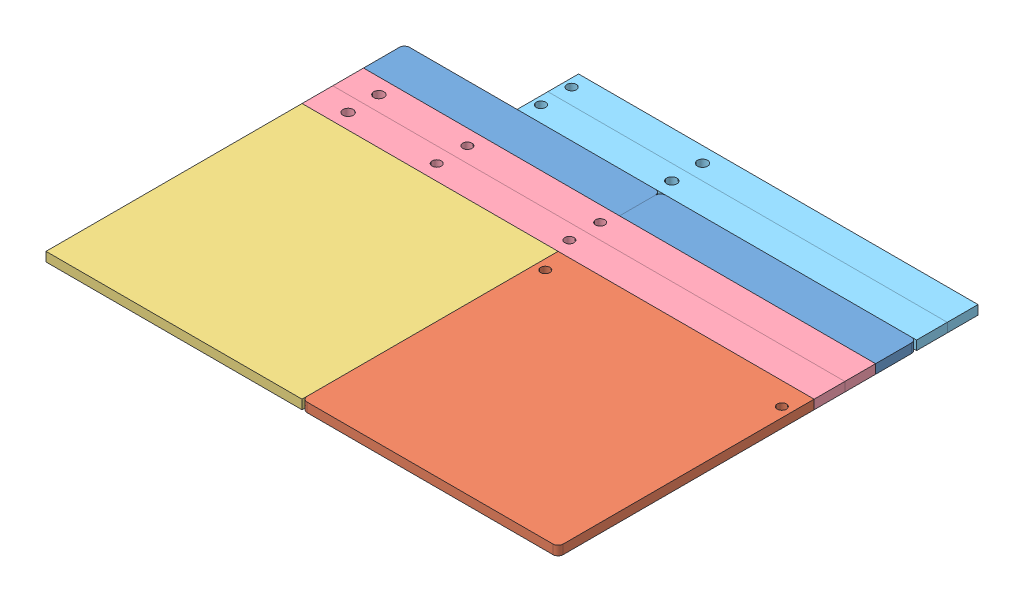
SolidWorks assembly cut sheet, configuration Default. Lengths in mm.
Overall size (1000 18 820).
8 component instances, 5 part files, 19 mates.
Components (placement in the parent):
- arm rest-1: arm rest [Default] at (390.54 276.275 -188.4241) size (500 18 80)
- arm rest-2: arm rest [Default] at (890.54 276.275 -188.4241) size (500 18 80)
- back-1: back [Default] at (1390.54 294.275 431.5759) x (-1 0 0) z (0 -1 0) size (500 500 18)
- seat-1: seat [Default] at (390.54 276.275 431.5759) size (500 18 500)
- leg-1: leg [Default] at (35221.2422 276.275 -8481.1823) x (0 1 0) z (0 0 1) size (18 1000 60)
- leg-2: leg [Default] at (35221.2422 276.275 -8541.1823) x (0 1 0) z (0 0 1) size (18 1000 60)
- leg 2-1: leg 2 [Default] at (-33440.1623 294.275 -8668.8365) x (0 -1 0) z (0 0 1) size (18 780 60)
- leg 2-2: leg 2 [Default] at (-33440.1623 294.275 -8728.8365) x (0 -1 0) z (0 0 1) size (18 780 60)
Mates (geometry in assembly coordinates):
- Coincident30: coincident: plane of back-1 through (1380.54 294.275 421.5759) normal (0 1 0); plane of seat-1 through (390.54 294.275 431.5759) normal (0 1 0)
- Coincident31: coincident: plane of back-1 through (1380.54 294.275 421.5759) normal (0 1 0); plane of leg-2 through (35221.2422 294.275 -8541.1823) normal (0 1 0)
- Coincident32: coincident: plane of back-1 through (1380.54 294.275 421.5759) normal (0 1 0); plane of leg-1 through (35221.2422 294.275 -8481.1823) normal (0 1 0)
- Coincident33: coincident: plane of back-1 through (1380.54 294.275 421.5759) normal (0 1 0); plane of leg 2-2 through (-33440.1623 294.275 -8728.8365) normal (0 1 0)
- Coincident34: coincident: plane of back-1 through (1380.54 294.275 421.5759) normal (0 1 0); plane of leg 2-1 through (-33440.1623 294.275 -8668.8365) normal (0 1 0)
- Coincident35: coincident: plane of back-1 through (1380.54 294.275 421.5759) normal (0 1 0); plane of arm rest-1 through (400.54 294.275 -258.4241) normal (0 1 0)
- Coincident36: coincident: plane of back-1 through (1380.54 294.275 421.5759) normal (0 1 0); plane of arm rest-2 through (900.54 294.275 -258.4241) normal (0 1 0)
- Coincident37: coincident: line of back-1 through (1390.54 294.275 -68.4241) axis (0 0 1); line of leg-1 through (1390.54 294.275 -68.4241) axis (0 0 -1)
- Coincident38: coincident: line of back-1 through (1390.54 294.275 -68.4241) axis (0 0 1); line of leg-2 through (1390.54 294.275 -128.4241) axis (0 0 -1)
- Coincident39: coincident: line of back-1 through (1390.54 294.275 -68.4241) axis (0 0 1); line of leg 2-2 through (1390.54 294.275 -388.4241) axis (0 0 1)
- Coincident40: coincident: line of back-1 through (1390.54 294.275 -68.4241) axis (0 0 1); line of leg 2-1 through (1390.54 294.275 -328.4241) axis (0 0 1)
- Coincident41: coincident: line of back-1 through (1390.54 294.275 -68.4241) axis (0 0 1); line of arm rest-2 through (1390.54 294.275 -188.4241) axis (0 0 -1)
- Coincident43: coincident: line of arm rest-1 through (890.54 294.275 -188.4241) axis (0 0 -1); line of arm rest-2 through (890.54 294.275 -258.4241) axis (0 0 1)
- Coincident44: coincident: line of arm rest-1 through (880.54 294.275 -268.4241) axis (-1 0 0); line of arm rest-2 through (1380.54 294.275 -268.4241) axis (-1 0 0)
- Coincident46: coincident: plane of back-1 through (1390.54 276.275 -68.4241) normal (0 0 -1); plane of leg-1 through (390.54 294.275 -68.4241) normal (0 0 1)
- Coincident47: coincident: plane of leg-1 through (390.54 294.275 -128.4241) normal (0 0 -1); plane of leg-2 through (390.54 294.275 -128.4241) normal (0 0 1)
- Coincident48: coincident: plane of arm rest-2 through (890.54 294.275 -188.4241) normal (0 0 1); plane of leg-2 through (390.54 294.275 -188.4241) normal (0 0 -1)
- Coincident49: coincident: plane of arm rest-2 through (900.54 294.275 -268.4241) normal (0 0 -1); plane of leg 2-1 through (1390.54 276.275 -268.4241) normal (0 0 1)
- Coincident50: coincident: plane of leg 2-1 through (1390.54 276.275 -328.4241) normal (0 0 -1); plane of leg 2-2 through (1390.54 276.275 -328.4241) normal (0 0 1)
